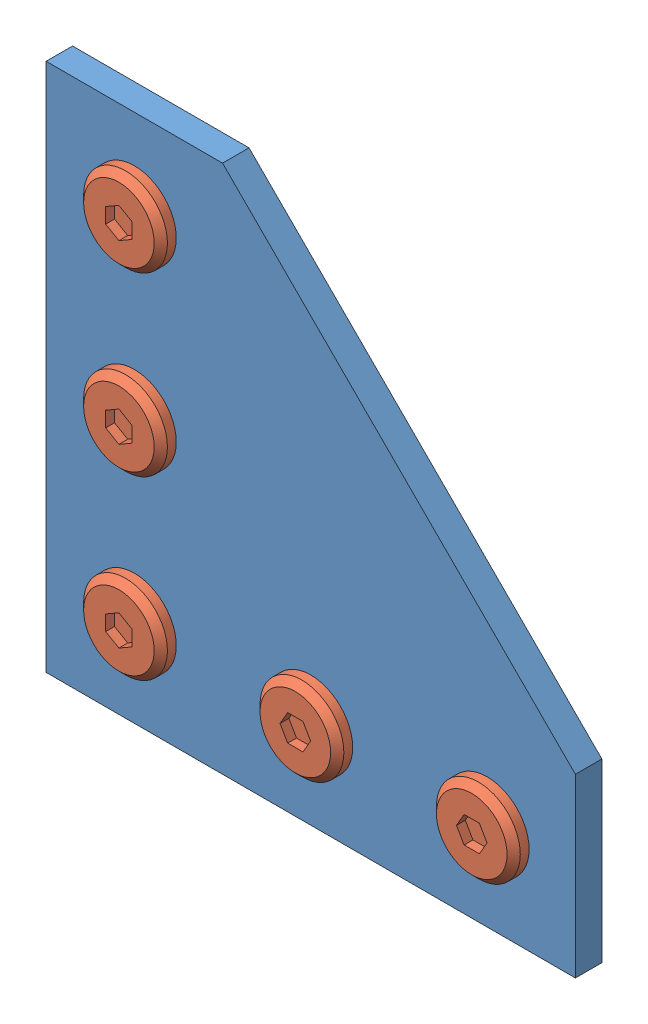
SolidWorks assembly 5 Hole 90 Degree Bracket with Bolts, configuration Default. Lengths in mm.
Overall size (60 60 10.1).
16 component instances, 3 part files, 12 mates.
Components (placement in the parent):
- 5 Hole 90 Degree Joining Plate-1: 5 Hole 90 Degree Joining Plate [Default] at (4.3285 16.0061 65.9875) size (60 60 3)
- 5mm x 8mm Bolt with Tee Nut-1: 5mm x 8mm Bolt with Tee Nut [Default] at (3.8516 58.2866 32.8937) x (0 0 -1) z (1 0 0) size (10.1 10 15)
  - 5mm x 8mm Low Profile Socket Head Screw-1: 5mm x 8mm Low Profile Socket Head Screw [5mm x 8mm Low Profile] at (-34.8438 7.7195 10.4769) size (10.1 9.5 9.5)
  - Tee nut-1: Tee nut [Default] at (-28.2938 2.7205 17.9769) x (0 0 -1) z (1 0 0) size (15 10 3.3)
- 5mm x 8mm Bolt with Tee Nut-2: 5mm x 8mm Bolt with Tee Nut [Default] at (3.8516 38.2866 32.8937) x (0 0 -1) z (1 0 0) size (10.1 10 15)
  - 5mm x 8mm Low Profile Socket Head Screw-1: 5mm x 8mm Low Profile Socket Head Screw [5mm x 8mm Low Profile] at (-34.8438 7.7195 10.4769) size (10.1 9.5 9.5)
  - Tee nut-1: Tee nut [Default] at (-28.2938 2.7205 17.9769) x (0 0 -1) z (1 0 0) size (15 10 3.3)
- 5mm x 8mm Bolt with Tee Nut-3: 5mm x 8mm Bolt with Tee Nut [Default] at (3.8516 18.2866 32.8937) x (0 0 -1) z (1 0 0) size (10.1 10 15)
  - 5mm x 8mm Low Profile Socket Head Screw-1: 5mm x 8mm Low Profile Socket Head Screw [5mm x 8mm Low Profile] at (-34.8438 7.7195 10.4769) size (10.1 9.5 9.5)
  - Tee nut-1: Tee nut [Default] at (-28.2938 2.7205 17.9769) x (0 0 -1) z (1 0 0) size (15 10 3.3)
- 5mm x 8mm Bolt with Tee Nut-4: 5mm x 8mm Bolt with Tee Nut [Default] at (42.048 15.5292 32.8937) x (0 0 -1) z (0 1 0) size (10.1 10 15)
  - 5mm x 8mm Low Profile Socket Head Screw-1: 5mm x 8mm Low Profile Socket Head Screw [5mm x 8mm Low Profile] at (-34.8438 7.7195 10.4769) size (10.1 9.5 9.5)
  - Tee nut-1: Tee nut [Default] at (-28.2938 2.7205 17.9769) x (0 0 -1) z (1 0 0) size (15 10 3.3)
- 5mm x 8mm Bolt with Tee Nut-5: 5mm x 8mm Bolt with Tee Nut [Default] at (62.048 15.5292 32.8937) x (0 0 -1) z (0 1 0) size (10.1 10 15)
  - 5mm x 8mm Low Profile Socket Head Screw-1: 5mm x 8mm Low Profile Socket Head Screw [5mm x 8mm Low Profile] at (-34.8438 7.7195 10.4769) size (10.1 9.5 9.5)
  - Tee nut-1: Tee nut [Default] at (-28.2938 2.7205 17.9769) x (0 0 -1) z (1 0 0) size (15 10 3.3)
Mates (geometry in assembly coordinates):
- Coincident1: coincident anti-aligned: plane of 5 Hole 90 Degree Joining Plate-1 through (4.3285 16.0061 65.9875) normal (0 0 1); plane of 5mm x 8mm Bolt with Tee Nut-1/5mm x 8mm Low Profile Socket Head Screw-1 through (14.3285 68.5061 65.9875) normal (0 0 -1)
- Coincident2: coincident anti-aligned: plane of 5 Hole 90 Degree Joining Plate-1 through (4.3285 16.0061 65.9875) normal (0 0 1); plane of 5mm x 8mm Bolt with Tee Nut-2/5mm x 8mm Low Profile Socket Head Screw-1 through (14.3285 48.5061 65.9875) normal (0 0 -1)
- Coincident3: coincident anti-aligned: plane of 5 Hole 90 Degree Joining Plate-1 through (4.3285 16.0061 65.9875) normal (0 0 1); plane of 5mm x 8mm Bolt with Tee Nut-3/5mm x 8mm Low Profile Socket Head Screw-1 through (11.8285 26.0061 65.9875) normal (0 0 -1)
- Coincident5: coincident anti-aligned: plane of 5 Hole 90 Degree Joining Plate-1 through (4.3285 16.0061 65.9875) normal (0 0 1); plane of 5mm x 8mm Bolt with Tee Nut-4/5mm x 8mm Low Profile Socket Head Screw-1 through (31.8285 26.0061 65.9875) normal (0 0 -1)
- Coincident6: coincident anti-aligned: plane of 5 Hole 90 Degree Joining Plate-1 through (4.3285 16.0061 65.9875) normal (0 0 1); plane of 5mm x 8mm Bolt with Tee Nut-5/5mm x 8mm Low Profile Socket Head Screw-1 through (51.8285 26.0061 65.9875) normal (0 0 -1)
- Concentric1: concentric aligned: cylinder of 5 Hole 90 Degree Joining Plate-1 through (54.3285 26.0061 62.9875) axis (0 0 1) radius 2.5; cylinder of 5mm x 8mm Bolt with Tee Nut-5/5mm x 8mm Low Profile Socket Head Screw-1 through (54.3285 26.0061 67.7375) axis (0 0 1) radius 4.75
- Concentric2: concentric anti-aligned: cylinder of 5 Hole 90 Degree Joining Plate-1 through (34.3285 26.0061 62.9875) axis (0 0 1) radius 2.5; cylinder of 5mm x 8mm Bolt with Tee Nut-4/Tee nut-1 through (34.3285 26.0061 62.8375) axis (0 0 -1) radius 2.6
- Concentric3: concentric anti-aligned: cylinder of 5 Hole 90 Degree Joining Plate-1 through (14.3285 26.0061 62.9875) axis (0 0 1) radius 2.5; cylinder of 5mm x 8mm Bolt with Tee Nut-3/Tee nut-1 through (14.3285 26.0061 62.8375) axis (0 0 -1) radius 2.6
- Concentric4: concentric anti-aligned: cylinder of 5 Hole 90 Degree Joining Plate-1 through (14.3285 46.0061 62.9875) axis (0 0 1) radius 2.5; cylinder of 5mm x 8mm Bolt with Tee Nut-2/Tee nut-1 through (14.3285 46.0061 62.8375) axis (0 0 -1) radius 2.6
- Concentric5: concentric anti-aligned: circle of 5 Hole 90 Degree Joining Plate-1; cylinder of 5mm x 8mm Bolt with Tee Nut-1/Tee nut-1 through (14.3285 66.0061 62.8375) axis (0 0 -1) radius 2.6
- Parallel1: parallel aligned: plane of 5 Hole 90 Degree Joining Plate-1 through (4.3285 16.0061 62.9875) normal (0 -1 0); plane of 5mm x 8mm Bolt with Tee Nut-5/Tee nut-1 through (59.3275 18.5061 59.5375) normal (0 -1 0)
- Parallel2: parallel aligned: plane of 5 Hole 90 Degree Joining Plate-1 through (4.3285 16.0061 62.9875) normal (-1 0 0); plane of 5mm x 8mm Bolt with Tee Nut-3/Tee nut-1 through (6.8285 21.0071 59.5375) normal (-1 0 0)
